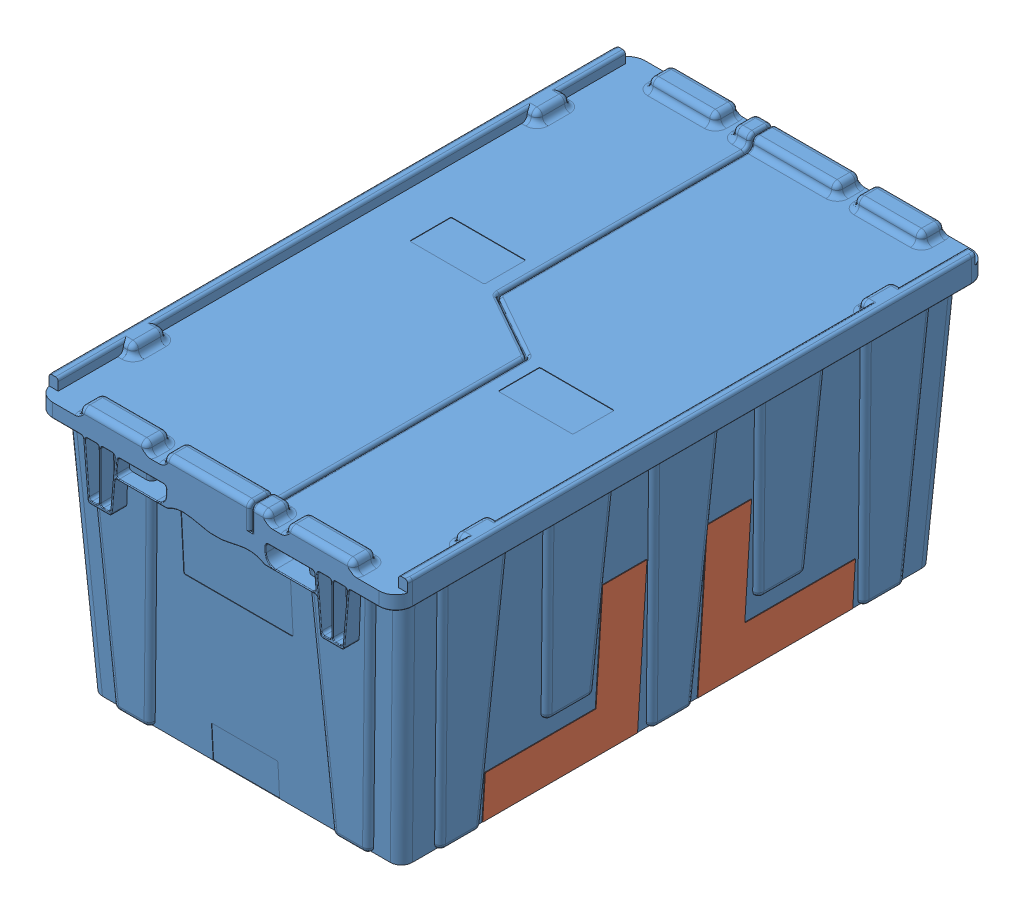
SolidWorks assembly YELLOW_TOTEASM_ASM, configuration Default. Lengths in mm.
Overall size (412.75 313.83 692.15).
5 component instances, 2 part files, 0 mates.
Components (placement in the parent):
- YELLOW_TOTE_1-1: YELLOW_TOTE_1 [Default] at (205.9881 -0.8503 339.3942) x (0 1 0) z (0 0 1) size (313.83 412.75 692.15)
- VISION_TARGET-1: VISION_TARGET [Default] at (384.175 0 374.2855) x (0.06111 0.998131 0) z (0.998131 -0.06111 0) size (177.8 177.8 0.79)
- VISION_TARGET-2: VISION_TARGET [Default] at (384.9673 -0.0485 305.1645) x (0.06111 0.998131 0) z (-0.998131 0.06111 0) size (177.8 177.8 0.79)
- VISION_TARGET-3: VISION_TARGET [Default] at (27.7827 -0.0485 374.2855) x (-0.06111 0.998131 0) z (0.998131 0.06111 0) size (177.8 177.8 0.79)
- VISION_TARGET-4: VISION_TARGET [Default] at (28.575 0 305.1645) x (-0.06111 0.998131 0) z (-0.998131 -0.06111 0) size (177.8 177.8 0.79)
